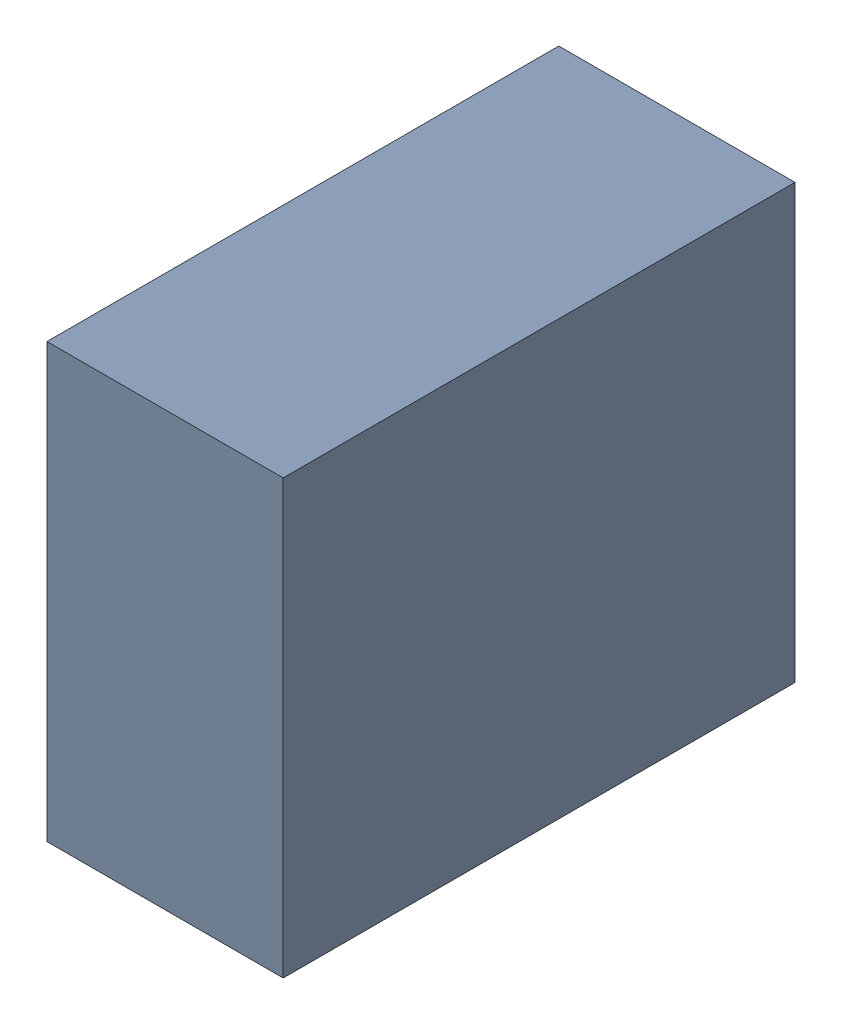
SolidWorks assembly C25_TDA4, configuration Standard. Lengths in mm.
Overall size (0.6 1.1 1.3).
2 component instances, 1 part files, 0 mates.
Components (placement in the parent):
- 885542376-1: 885542376 [Standard] at (-2.02 -42.09 0) size (0.6 1.1 1.3)
  - Extruded_25-1: Extruded_25 [Standard] at origin size (0.6 1.1 1.3)
